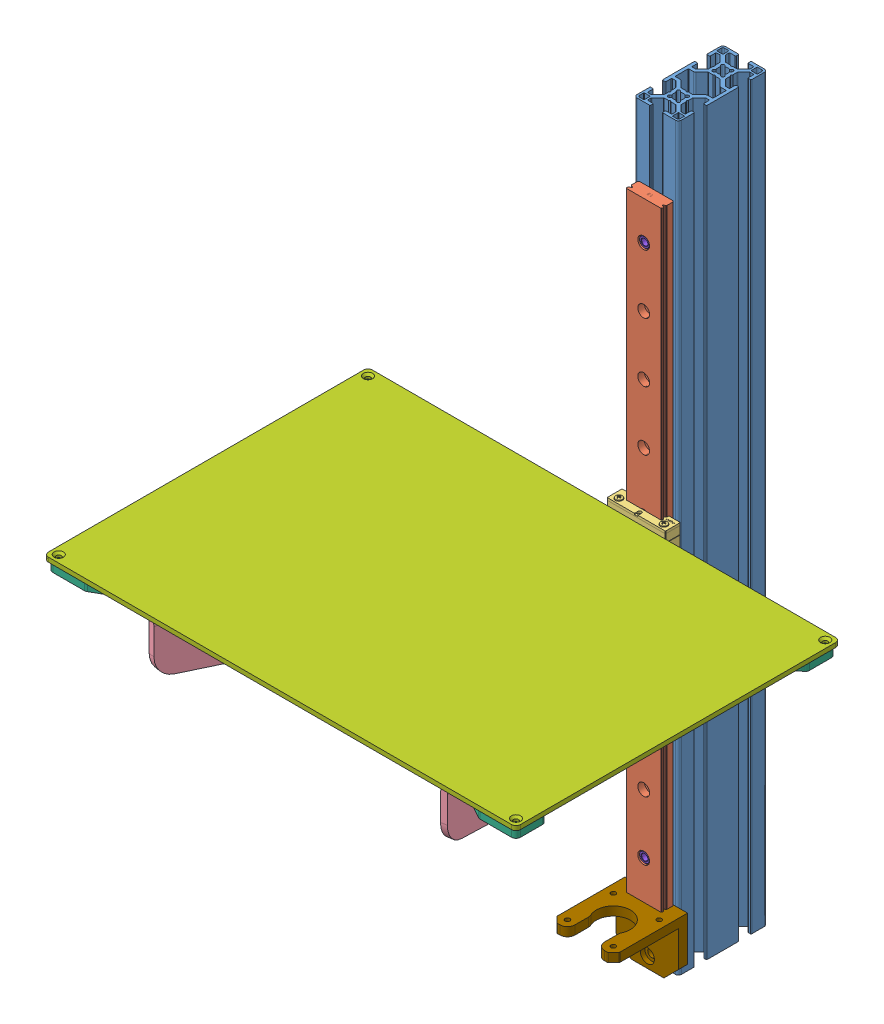
SolidWorks assembly Z-Axis Asm, configuration Default. Lengths in mm.
Overall size (319 500 314.5).
11 component instances, 9 part files, 27 mates.
Components (placement in the parent):
- 8020-30-3060 X 4000-1: 8020-30-3060 X 4000 [30-3060] x (0 0 -1) z (0 -1 0) size (60 30 500)
- Z-Axis_Hiwin Rail MGW12H1R412Z0HM-1: Z-Axis_Hiwin Rail MGW12H1R412Z0HM [Default] at (0 40 30) size (40 412 14) (flexible)
  - MGW12H1R412Z0HM_FILE(2)-1: MGW12H1R412Z0HM_FILE(2) [Default] at origin size (24 412 8.5)
  - MGW12H1R412Z0HM_FILE-1: MGW12H1R412Z0HM_FILE [Default] at (0 124.1553 0) size (40 61.58 10.6)
- MS-BED-BRACKET 1.4-1: MS-BED-BRACKET 1.4 [Default] at (0 247.3563 78) x (1 0 0) z (0 1 0) size (263.8 198.64 68)
- Z-Axis Bed Bearing Bracket-1: Z-Axis Bed Bearing Bracket [Default] at (0 239.8563 44) x (-1 0 0) z (0 1 0) size (115 30 60)
- Z-Axis Bed Plate-1: Z-Axis Bed Plate [Default] at (0.2032 283.8563 174.9999) x (-1 0 0) z (0 -1 0) size (316 216 6)
- 300X200MM XL ALUMINUM BUILD PLATE-1: 300X200MM XL ALUMINUM BUILD PLATE [Default] at (0.2032 283.8563 174.9999) size (319 3 219)
- MS-Z-STOP 1.0-1: MS-Z-STOP 1.0 [Default] at (0 426 34) x (0.997147 -0.075487 0) z (-0.075487 -0.997147 0) size (7 4 7)
- MS-Z-STOP 1.0-2: MS-Z-STOP 1.0 [Default] at (0 66 34) x (0.996502 0.083568 0) z (0.083568 -0.996502 0) size (7 4 7)
- Z-Axis Angle Motor Bracket-1: Z-Axis Angle Motor Bracket [Default] at (0 40 30) x (1 0 0) z (0 1 0) size (42.3 50 40)
Mates (geometry in assembly coordinates):
- Coincident3: coincident anti-aligned: plane of MS-BED-BRACKET 1.4-1 through (97.188 277.8563 173.934) normal (0 1 0); plane of Z-Axis Bed Plate-1 through (0.2032 277.8563 174.9999) normal (0 -1 0)
- Width1: width: plane of MS-BED-BRACKET 1.4-1 through (111.9005 277.8563 251.6686) normal (0 0 1); plane of MS-BED-BRACKET 1.4-1 through (121.9005 277.8563 256.4686) normal (0 0 -1); cylinder of Z-Axis Bed Plate-1 through (117.1036 283.8563 254.0686) axis (0 -1 0) radius 1.666
- Width2: width: plane of MS-BED-BRACKET 1.4-1 through (-86.9878 277.8563 115.1817) normal (0 0 -1); plane of MS-BED-BRACKET 1.4-1 through (-96.9878 277.8563 110.3817) normal (0 0 1); cylinder of Z-Axis Bed Plate-1 through (-91.7846 283.8563 112.7817) axis (0 -1 0) radius 1.666
- Slot1: slot aligned: plane of MS-BED-BRACKET 1.4-1 through (96.9878 277.8563 115.1817) normal (0 0 -1); cylinder of Z-Axis Bed Plate-1 through (92.1909 283.8563 112.7817) axis (0 -1 0) radius 1.666; cylinder of MS-BED-BRACKET 1.4-1 through (86.9878 277.8563 112.7817) axis (0 -1 0) radius 2.4
- Concentric5: concentric anti-aligned: cylinder of MS-BED-BRACKET 1.4-1 through (-50 262.3563 78) axis (0 0 -1) radius 2.1; cylinder of Z-Axis Bed Bearing Bracket-1 through (-50 262.3563 44) axis (0 0 1) radius 1.666
- Concentric6: concentric anti-aligned: cylinder of MS-BED-BRACKET 1.4-1 through (50 262.3563 78) axis (0 0 -1) radius 2.1; cylinder of Z-Axis Bed Bearing Bracket-1 through (50 262.3563 44) axis (0 0 1) radius 1.666
- Coincident4: coincident anti-aligned: plane of MS-BED-BRACKET 1.4-1 through (0 239.8563 74) normal (0 0 -1); plane of Z-Axis Bed Bearing Bracket-1 through (-50 262.3563 74) normal (0 0 1)
- Concentric7: concentric aligned: cylinder of Z-Axis_Hiwin Rail MGW12H1R412Z0HM-1/MGW12H1R412Z0HM_FILE-1 through (14 253.8563 42.2) axis (0 0 1) radius 1.25; cylinder of Z-Axis Bed Bearing Bracket-1 through (14 253.8563 44) axis (0 0 1) radius 1.6
- Concentric8: concentric aligned: cylinder of Z-Axis_Hiwin Rail MGW12H1R412Z0HM-1/MGW12H1R412Z0HM_FILE-1 through (14 225.8563 42.2) axis (0 0 1) radius 1.25; cylinder of Z-Axis Bed Bearing Bracket-1 through (14 225.8563 44) axis (0 0 1) radius 1.6
- Coincident5: coincident anti-aligned: plane of Z-Axis_Hiwin Rail MGW12H1R412Z0HM-1/MGW12H1R412Z0HM_FILE-1 through (8 217.0563 44) normal (0 0 1); plane of Z-Axis Bed Bearing Bracket-1 through (-50 262.3563 44) normal (0 0 -1)
- Distance1: distance = 4.064 mm: cylinder of Z-Axis Bed Plate-1 through (-91.7846 283.8563 112.7817) axis (0 -1 0) radius 1.666; line of MS-BED-BRACKET 1.4-1 through (-96.9878 277.8563 110.3817) axis (0 -1 0)
- Coincident73: coincident anti-aligned: plane of Z-Axis Bed Plate-1 through (0.2032 283.8563 174.9999) normal (0 1 0); plane of 300X200MM XL ALUMINUM BUILD PLATE-1 through (156.7032 283.8563 68.4999) normal (0 -1 0)
- Concentric67: concentric anti-aligned: cylinder of Z-Axis Bed Plate-1 through (-154.2968 283.8563 279.4999) axis (0 -1 0) radius 1.6; cylinder of 300X200MM XL ALUMINUM BUILD PLATE-1 through (-154.2968 286.8563 279.4999) axis (0 1 0) radius 1.7
- Concentric68: concentric anti-aligned: cylinder of Z-Axis Bed Plate-1 through (154.7032 283.8563 279.4999) axis (0 -1 0) radius 1.6; cylinder of 300X200MM XL ALUMINUM BUILD PLATE-1 through (154.7032 286.8563 279.4999) axis (0 1 0) radius 1.7
- Concentric69: concentric aligned: cylinder of Z-Axis_Hiwin Rail MGW12H1R412Z0HM-1/MGW12H1R412Z0HM_FILE(2)-1 through (0 426 41) axis (0 0 1) radius 4; cylinder of MS-Z-STOP 1.0-1 through (0 426 34) axis (0 0 1) radius 3.5
- Coincident74: coincident anti-aligned: plane of Z-Axis_Hiwin Rail MGW12H1R412Z0HM-1/MGW12H1R412Z0HM_FILE(2)-1 through (4 421.893 34) normal (0 0 1); plane of MS-Z-STOP 1.0-1 through (0 426 34) normal (0 0 -1)
- Concentric70: concentric aligned: cylinder of Z-Axis_Hiwin Rail MGW12H1R412Z0HM-1/MGW12H1R412Z0HM_FILE(2)-1 through (0 66 41) axis (0 0 1) radius 4; cylinder of MS-Z-STOP 1.0-2 through (0 66 34) axis (0 0 1) radius 3.5
- Coincident75: coincident anti-aligned: plane of Z-Axis_Hiwin Rail MGW12H1R412Z0HM-1/MGW12H1R412Z0HM_FILE(2)-1 through (4 61.893 34) normal (0 0 1); plane of MS-Z-STOP 1.0-2 through (0 66 34) normal (0 0 -1)
- Coincident76: coincident anti-aligned: plane of Z-Axis Angle Motor Bracket-1 through (0 40 30) normal (0 1 0); plane of Z-Axis_Hiwin Rail MGW12H1R412Z0HM-1/MGW12H1R412Z0HM_FILE(2)-1 through (-12 40 38.5) normal (0 -1 0)
- Coincident77: coincident anti-aligned: plane of 8020-30-3060 X 4000-1 through (12.9934 500 30) normal (0 0 1); plane of Z-Axis_Hiwin Rail MGW12H1R412Z0HM-1/MGW12H1R412Z0HM_FILE(2)-1 through (11.4 40 30) normal (0 0 -1)
- Width16: width: plane of 8020-30-3060 X 4000-1 through (-15 500 27.9934) normal (-1 0 0); plane of 8020-30-3060 X 4000-1 through (15 500 19.572) normal (1 0 0); cylinder of Z-Axis_Hiwin Rail MGW12H1R412Z0HM-1/MGW12H1R412Z0HM_FILE(2)-1 through (0 66 41) axis (0 0 1) radius 4
- Coincident80: coincident anti-aligned: plane of 8020-30-3060 X 4000-1 through (-4.572 500 30) normal (0 0 1); plane of Z-Axis Angle Motor Bracket-1 through (0 0 30) normal (0 0 -1)
- Width17: width aligned: plane of Z-Axis Angle Motor Bracket-1 through (21.15 20 55) normal (1 0 0); plane of Z-Axis Angle Motor Bracket-1 through (-21.15 20 55) normal (-1 0 0); plane of 8020-30-3060 X 4000-1 through (15 500 -10.428) normal (1 0 0); plane of 8020-30-3060 X 4000-1 through (-15 500 10.428) normal (-1 0 0)
- Coincident81: coincident anti-aligned: plane of 8020-30-3060 X 4000-1 through (0 0 0) normal (0 -1 0); plane of assembly through (0 0 0) normal (0 1 0)
- Coincident82: coincident aligned: plane of 8020-30-3060 X 4000-1 through (0 0 0) normal (1 0 0); plane of assembly through (0 0 0) normal (1 0 0)
- Coincident83: coincident anti-aligned: plane of 8020-30-3060 X 4000-1 through (0 0 0) normal (0 0 -1); plane of assembly through (0 0 0) normal (0 0 1)
- Coincident84: coincident aligned: plane of 8020-30-3060 X 4000-1 through (-14.492 0 10.428) normal (0 -1 0); plane of Z-Axis Angle Motor Bracket-1 through (0 0 36) normal (0 -1 0)
